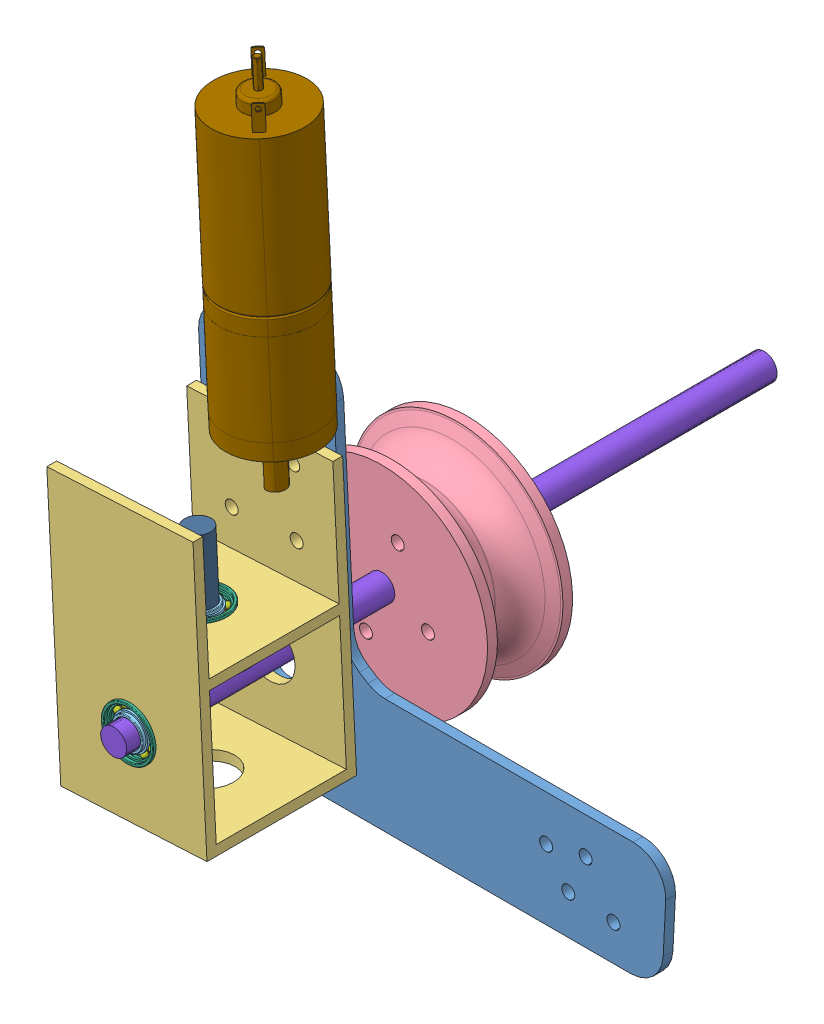
SolidWorks assembly full_assambly, configuration Default. Lengths in mm.
Overall size (507.36 374.75 200).
34 component instances, 10 part files, 18 mates.
Components (placement in the parent):
- thoda sa exturaded part_final_with_mount_motor side-1: thoda sa exturaded part_final_with_mount_motor side [Default] at (-28.5016 -65.023 268.4973) size (490.94 374.75 6.04)
- straight bevel pinion_am-1: straight bevel pinion_am [Metric - Straight bevel pinion 1.25M20PT 20GT 20PA 7FW ---20O15H18MD8N] at (41.9881 146.7948 311.8291) x (0 0 -1) z (0.99907 0.043128 0) size (11.32 26.67 26.67)
- new_gearbox_bevel-1: new_gearbox_bevel [Default] at (43.217 123.0766 298.0157) x (0 0 -1) z (0.99866 0.051744 0) size (46 83 45)
- wheels_negative_compy-1: wheels_negative_compy [Default] at (92.6653 129.3367 230.4868) x (0 0 -1) z (0.325712 0.945469 0) size (26.15 65 65)
- F688ZZ_assembly-1: F688ZZ_assembly [Default] at (41.9881 146.7948 316.9157) x (-0.898975 -0.438001 0) z (-0.438001 0.898975 0) size (20.89 5 20.89)
  - F688ZZ_shaft-1: F688ZZ_shaft [Default] at origin size (10.7 5 10.7)
  - F688ZZ_Housing-1: F688ZZ_Housing [Default] x (0.984312 0 0.176438) z (-0.176438 0 0.984312) size (18 5 18)
  - F688ZZ_Ball-1: F688ZZ_Ball [Default] at (5.5752 2.5 -2.1489) x (0.959238 0.232099 0.161224) z (-0.142462 -0.095558 0.985177) size (2 2 2)
  - F688ZZ_Ball-20: F688ZZ_Ball [Default] at (3.2474 2.5 -5.0155) x (0.870805 0.232099 -0.433393) z (0.463818 -0.095558 0.880762) size (2 2 2)
  - F688ZZ_Ball-21: F688ZZ_Ball [Default] at (-0.3209 2.5 -5.9664) x (0.449753 0.232099 -0.862469) z (0.892936 -0.095558 0.439926) size (2 2 2)
  - F688ZZ_Ball-22: F688ZZ_Ball [Default] at (-3.7665 2.5 -4.6383) x (-0.143088 0.232099 -0.96211) z (0.980982 -0.095558 -0.168947) size (2 2 2)
  - F688ZZ_Ball-23: F688ZZ_Ball [Default] at (-5.7735 2.5 -1.5385) x (-0.681275 0.232099 -0.694258) z (0.694326 -0.095558 -0.713288) size (2 2 2)
  - F688ZZ_Ball-24: F688ZZ_Ball [Default] at (-5.5752 2.5 2.1489) x (-0.959238 0.232099 -0.161224) z (0.142462 -0.095558 -0.985177) size (2 2 2)
  - F688ZZ_Ball-25: F688ZZ_Ball [Default] at (-3.2474 2.5 5.0155) x (-0.870805 0.232099 0.433393) z (-0.463818 -0.095558 -0.880762) size (2 2 2)
  - F688ZZ_Ball-26: F688ZZ_Ball [Default] at (0.3209 2.5 5.9664) x (-0.449753 0.232099 0.862469) z (-0.892936 -0.095558 -0.439926) size (2 2 2)
  - F688ZZ_Ball-27: F688ZZ_Ball [Default] at (3.7665 2.5 4.6383) x (0.143088 0.232099 0.96211) z (-0.980982 -0.095558 0.168947) size (2 2 2)
  - F688ZZ_Ball-28: F688ZZ_Ball [Default] at (5.7735 2.5 1.5385) x (0.681275 0.232099 0.694258) z (-0.694326 -0.095558 0.713288) size (2 2 2)
- straight bevel pinion_am-4: straight bevel pinion_am [Metric - Straight bevel pinion 1.25M20PT 20GT 20PA 7FW ---20O15H18MD8N] at (41.3121 159.8407 298.0157) x (0.051744 -0.99866 0) z (-0.773641 -0.040085 -0.632355) size (11.32 26.67 26.67)
- F688ZZ_assembly-4: F688ZZ_assembly [Default] at (41.0489 164.9205 298.0157) x (0.837385 0.043387 0.544889) z (-0.544159 -0.028195 0.838508) size (20.89 5 20.89)
  - F688ZZ_shaft-1: F688ZZ_shaft [Default] at origin size (10.7 5 10.7)
  - F688ZZ_Housing-1: F688ZZ_Housing [Default] x (0.984312 0 0.176438) z (-0.176438 0 0.984312) size (18 5 18)
  - F688ZZ_Ball-1: F688ZZ_Ball [Default] at (5.5752 2.5 -2.1489) x (0.959238 0.232099 0.161224) z (-0.142462 -0.095558 0.985177) size (2 2 2)
  - F688ZZ_Ball-20: F688ZZ_Ball [Default] at (3.2474 2.5 -5.0155) x (0.870805 0.232099 -0.433393) z (0.463818 -0.095558 0.880762) size (2 2 2)
  - F688ZZ_Ball-21: F688ZZ_Ball [Default] at (-0.3209 2.5 -5.9664) x (0.449753 0.232099 -0.862469) z (0.892936 -0.095558 0.439926) size (2 2 2)
  - F688ZZ_Ball-22: F688ZZ_Ball [Default] at (-3.7665 2.5 -4.6383) x (-0.143088 0.232099 -0.96211) z (0.980982 -0.095558 -0.168947) size (2 2 2)
  - F688ZZ_Ball-23: F688ZZ_Ball [Default] at (-5.7735 2.5 -1.5385) x (-0.681275 0.232099 -0.694258) z (0.694326 -0.095558 -0.713288) size (2 2 2)
  - F688ZZ_Ball-24: F688ZZ_Ball [Default] at (-5.5752 2.5 2.1489) x (-0.959238 0.232099 -0.161224) z (0.142462 -0.095558 -0.985177) size (2 2 2)
  - F688ZZ_Ball-25: F688ZZ_Ball [Default] at (-3.2474 2.5 5.0155) x (-0.870805 0.232099 0.433393) z (-0.463818 -0.095558 -0.880762) size (2 2 2)
  - F688ZZ_Ball-26: F688ZZ_Ball [Default] at (0.3209 2.5 5.9664) x (-0.449753 0.232099 0.862469) z (-0.892936 -0.095558 -0.439926) size (2 2 2)
  - F688ZZ_Ball-27: F688ZZ_Ball [Default] at (3.7665 2.5 4.6383) x (0.143088 0.232099 0.96211) z (-0.980982 -0.095558 0.168947) size (2 2 2)
  - F688ZZ_Ball-28: F688ZZ_Ball [Default] at (5.7735 2.5 1.5385) x (0.681275 0.232099 0.694258) z (-0.694326 -0.095558 0.713288) size (2 2 2)
- 8mm shaft-1: 8mm shaft [Default] at (41.9881 146.7948 126.0157) x (-0.182211 0.98326 0) z (0 0 1) size (8 8 200)
- Planatary motor 10 rpm-1: Planatary motor 10 rpm [Default] at (63.9619 272.1875 301.0913) x (0.051744 -0.99866 0) z (0.709173 0.036744 0.704076) size (111.5 28 28)
- 8mm shaft._for motor-1: 8mm shaft._for motor [Default] at (39.7841 189.3313 298.0157) x (0.953967 0.049428 0.295811) z (0.051744 -0.99866 0) size (8 8 35)
Mates (geometry in assembly coordinates):
- Coincident5: coincident anti-aligned: plane of thoda sa exturaded part_final_with_mount_motor side-1 through (48.6975 219.2663 275.0157) normal (0 0 1); plane of new_gearbox_bevel-1 through (65.5316 127.2369 275.0157) normal (0 0 -1)
- Tangent2: tangent anti-aligned: plane of thoda sa exturaded part_final_with_mount_motor side-1 through (26.6175 211.5358 275.0157) normal (0.99866 0.051744 0); cylinder of new_gearbox_bevel-1 through (30.2833 179.4386 285.0157) axis (0 0 -1) radius 2
- Tangent3: tangent anti-aligned: plane of thoda sa exturaded part_final_with_mount_motor side-1 through (46.5908 212.5707 275.0157) normal (0.99866 0.051744 0); cylinder of new_gearbox_bevel-1 through (50.2565 180.4734 285.0157) axis (0 0 -1) radius 2
- Concentric1: concentric aligned: cylinder of new_gearbox_bevel-1 through (41.9881 146.7948 275.0157) axis (0 0 1) radius 7.8; cylinder of wheels_negative_compy-1 through (41.9881 146.7948 261.8298) axis (0 0 1) radius 2.5
- Concentric3: concentric aligned: cylinder of straight bevel pinion_8mm-1 through (41.9881 146.7948 293.829) axis (0 0 1) radius 4; cylinder of new_gearbox_bevel-1 through (41.9881 146.7948 275.0157) axis (0 0 1) radius 7.8
- Distance4: distance = 2 mm anti-aligned: plane of straight bevel pinion_8mm-1 through (41.9881 146.7948 316.0157) normal (0 0 1); plane of new_gearbox_bevel-1 through (18.7809 159.8615 318.0157) normal (0 0 -1)
- Concentric5: concentric aligned: cylinder of new_gearbox_bevel-1 through (41.9881 146.7948 275.0157) axis (0 0 1) radius 7.8; cylinder of F688ZZ_assembly-1/F688ZZ_Housing-1 through (41.9881 146.7948 318.0157) axis (0 0 1) radius 8
- Coincident8: coincident anti-aligned: plane of new_gearbox_bevel-1 through (18.7809 159.8615 318.0157) normal (0 0 -1); plane of F688ZZ_assembly-1/F688ZZ_Housing-1 through (41.9881 146.7948 318.0157) normal (0 0 1)
- Concentric7: concentric anti-aligned: cylinder of new_gearbox_bevel-1 through (40.4746 176.0056 298.0157) axis (0.051744 -0.99866 0) radius 7.8; cylinder of straight bevel pinion_8mm-4 through (42.2435 141.8647 298.0157) axis (-0.051744 0.99866 0) radius 4
- Distance5: distance = 2 mm anti-aligned: plane of straight bevel pinion_8mm-4 through (41.0955 164.0217 298.0157) normal (-0.051744 0.99866 0); plane of new_gearbox_bevel-1 through (40.992 166.019 298.0157) normal (0.051744 -0.99866 0)
- Concentric8: concentric anti-aligned: cylinder of new_gearbox_bevel-1 through (40.4746 176.0056 298.0157) axis (0.051744 -0.99866 0) radius 7.8; cylinder of F688ZZ_assembly-4/F688ZZ_Housing-1 through (40.992 166.019 298.0157) axis (-0.051744 0.99866 0) radius 8
- Coincident10: coincident anti-aligned: plane of new_gearbox_bevel-1 through (40.992 166.019 298.0157) normal (0.051744 -0.99866 0); plane of F688ZZ_assembly-4/F688ZZ_Housing-1 through (40.992 166.019 298.0157) normal (-0.051744 0.99866 0)
- Concentric9: concentric aligned: cylinder of F688ZZ_assembly-1/F688ZZ_shaft-1 through (41.9881 146.7948 321.9157) axis (0 0 -1) radius 4; cylinder of 8mm shaft-1 through (41.9881 146.7948 326.0157) axis (0 0 -1) radius 4
- Distance6: distance = 5 mm aligned: plane of 8mm shaft-1 through (41.9881 146.7948 326.0157) normal (0 0 1); plane of new_gearbox_bevel-1 through (65.5316 127.2369 321.0157) normal (0 0 1)
- Concentric10: concentric: cylinder of new_gearbox_bevel-1 through (66.2903 227.2478 301.0913) axis (-0.051744 0.99866 0) radius 10.5; circle of Planatary motor 10 rpm-1
- Coincident14: coincident: plane of new_gearbox_bevel-1 through (66.1351 230.2438 301.0913) normal (-0.051744 0.99866 0); plane of Planatary motor 10 rpm-1 through (75.9438 230.752 291.185) normal (0.051744 -0.99866 0)
- Concentric11: concentric anti-aligned: cylinder of F688ZZ_assembly-4/F688ZZ_shaft-1 through (40.7902 169.9138 298.0157) axis (0.051744 -0.99866 0) radius 4; cylinder of 8mm shaft._for motor-1 through (41.5952 154.3782 298.0157) axis (-0.051744 0.99866 0) radius 4
- Coincident15: coincident aligned: plane of straight bevel pinion_8mm-4 through (41.5952 154.3782 298.0157) normal (0.051744 -0.99866 0); plane of 8mm shaft._for motor-1 through (41.5952 154.3782 298.0157) normal (0.051744 -0.99866 0)
